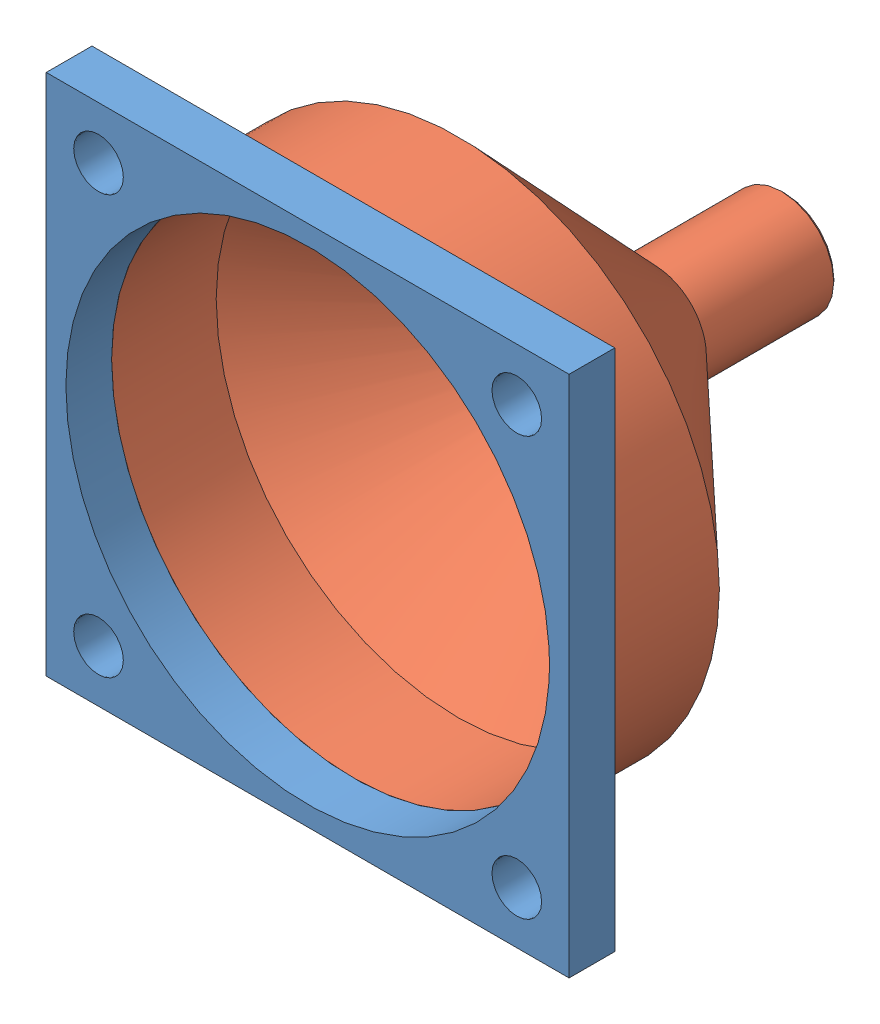
SolidWorks assembly Fan_assembly, configuration Default. Lengths in mm.
Overall size (40 40 36.5).
2 component instances, 2 part files, 2 mates.
Components (placement in the parent):
- Fan_base-1: Fan_base [Default] at (-47.1543 26.4065 31.6395) size (40 40 3.5)
- Fan_funnel-1: Fan_funnel [Default] at (-27.1543 6.4065 23.6395) size (40 40 33)
Mates (geometry in assembly coordinates):
- Coincident4: coincident anti-aligned: plane of Fan_base-1 through (-47.1543 26.4065 31.6395) normal (0 0 -1); plane of Fan_funnel-1 through (-45.6543 6.4065 31.6395) normal (0 0 1)
- Concentric1: concentric aligned: circle of Fan_base-1; cylinder of Fan_funnel-1 through (-27.1543 6.4065 23.6395) axis (0 0 1) radius 20
